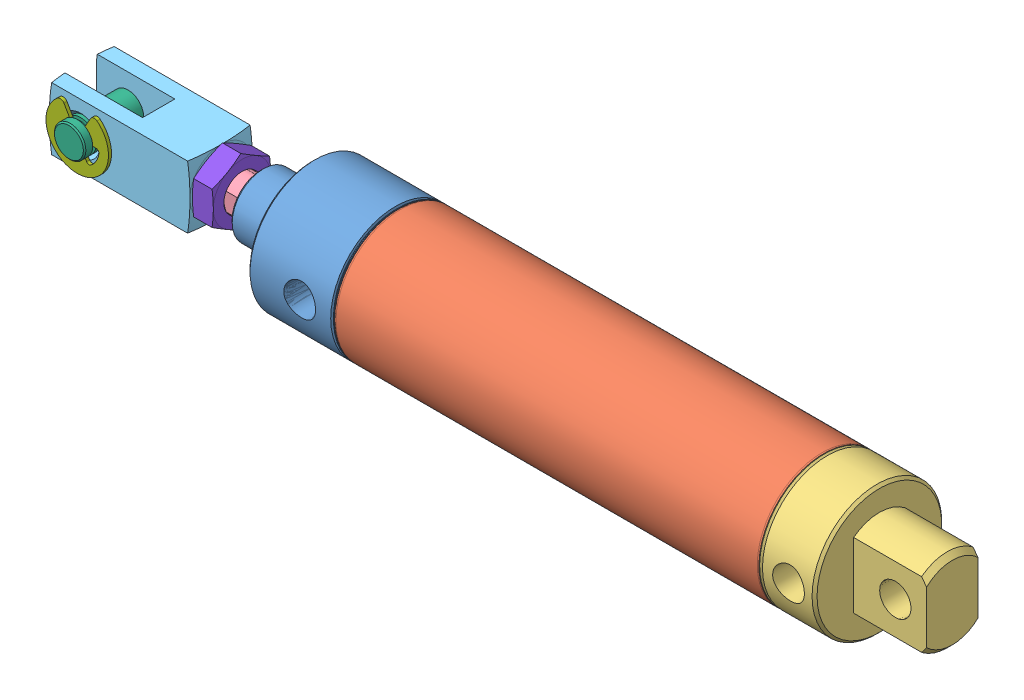
SolidWorks assembly 173_8-DP(F,D-231-1), configuration Default. Lengths in mm.
Overall size (266.64 39.54 39.54).
11 component instances, 10 part files, 26 mates.
Components (placement in the parent):
- 173_8-DPC(F,D-231-1)0000_0_dummy-1: 173_8-DPC(F,D-231-1)0000_0_dummy [Default] at origin
- 17R000-0_rod_guide-1: 17R000-0_rod_guide [Default] at origin size (47.62 39.54 39.54)
- 17R-5_10250C-1: 17R-5_10250C [Default] at (42.2275 0 0) size (131.44 39.54 39.54)
- 17P0000_rear_head-1: 17P0000_rear_head [Default] at (166.497 0 0) size (44.45 39.54 39.54)
- C-173_8-DP0_rod-1: C-173_8-DP0_rod [Default] x (1 0 0) z (0 0 -1) size (191.9 38.29 38.29)
- D-231-1-dummy-1: D-231-1-dummy [Default] at (-45.2628 0 0) x (1 0 0) z (0 0 -1)
- D-14053-1: D-14053 [Default] at (-45.2628 0 0) size (44.63 19.05 19.05)
- D-8383-1: D-8383 [Default] at (-45.2628 0 0) x (0 0 -1) z (-1 0 0) size (26.19 9.56 9.56)
- D-5867-1: D-5867 [Default] at (-45.2628 0 -10.1029) x (-1 0 0) z (0 0 1) size (19.05 17.19 0.93)
- D-5867-2: D-5867 [Default] at (-45.2628 0 10.1029) x (-1 0 0) z (0 0 1) size (19.05 17.19 0.93)
- D-154-1: D-154 [Default] at (-11.938 0 0) x (0 0 1) z (-1 0 0) size (17.53 20.24 6.35)
Mates (geometry in assembly coordinates):
- Distance2: distance = 0 mm aligned: plane of 17R000-0_rod_guide-1 through (0 0 0) normal (1 0 0); plane of 173_8-DPC(F,D-231-1)0000_0_dummy-1 through (0 0 0) normal (1 0 0)
- Coincident1: coincident aligned: line of 173_8-DPC(F,D-231-1)0000_0_dummy-1 through (80.9 0 0) axis (-1 0 0); line of 17R000-0_rod_guide-1 through (80.9 0 0) axis (-1 0 0)
- Angle3: planar angle = 0 rad aligned: plane of 17R000-0_rod_guide-1 through (0 0 0) normal (0 0 -1); plane of 173_8-DPC(F,D-231-1)0000_0_dummy-1 through (0 0 0) normal (0 0 -1)
- Distance4: distance = 0 mm aligned: plane of 17R-5_10250C-1 through (42.2275 0 0) normal (1 0 0); plane of 17R000-0_rod_guide-1 through (42.2275 0 0) normal (1 0 0)
- Coincident2: coincident aligned: line of 17R000-0_rod_guide-1 through (80.9 0 0) axis (-1 0 0); line of 17R-5_10250C-1 through (123.1275 0 0) axis (-1 0 0)
- Angle6: planar angle = 0 rad aligned: plane of 17R-5_10250C-1 through (42.2275 0 0) normal (0 0 -1); plane of 17R000-0_rod_guide-1 through (0 0 0) normal (0 0 -1)
- Distance6: distance = 0 mm aligned: plane of 17P0000_rear_head-1 through (171.831 0 0) normal (1 0 0); plane of 17R-5_10250C-1 through (171.831 0 0) normal (1 0 0)
- Coincident3: coincident aligned: line of 17R-5_10250C-1 through (123.1275 0 0) axis (-1 0 0); line of 17P0000_rear_head-1 through (247.397 0 0) axis (-1 0 0)
- Angle9: planar angle = 0.000031 rad aligned: plane of 17P0000_rear_head-1 through (166.497 0 0) normal (0 0 -1); plane of 17R-5_10250C-1 through (42.2275 0 0) normal (0 0 -1)
- LimitDistance2: limit distance = 0 mm aligned: plane of C-173_8-DP0_rod-1; plane of 17R000-0_rod_guide-1 through (0 0 0) normal (1 0 0)
- Coincident5: coincident aligned: line of 17R000-0_rod_guide-1 through (80.9 0 0) axis (-1 0 0); line of C-173_8-DP0_rod-1 through (80.9 0 0) axis (-1 0 0)
- Distance9: distance = 0 mm aligned: plane of D-231-1-dummy-1; plane of C-173_8-DP0_rod-1
- Coincident6: coincident aligned: line of C-173_8-DP0_rod-1 through (80.9 0 0) axis (-1 0 0); line of D-231-1-dummy-1 through (35.6372 0 0) axis (-1 0 0)
- Angle15: planar angle = 0 rad aligned: plane of D-231-1-dummy-1 through (-45.2628 0 0) normal (0 0 1); plane of C-173_8-DP0_rod-1 through (0 0 0) normal (0 0 1)
- Distance10: distance = 0 mm anti-aligned: plane of D-14053-1 through (-45.2628 0 0) normal (0 0 1); plane of D-231-1-dummy-1 through (-45.2628 0 0) normal (0 0 -1)
- Coincident7: coincident anti-aligned: line of D-231-1-dummy-1 through (-45.2628 0 -80.9) axis (0 0 1); line of D-14053-1 through (-45.2628 0 80.9) axis (0 0 -1)
- Angle18: planar angle = 0 rad aligned: plane of D-14053-1 through (-45.2628 0 0) normal (1 0 0); plane of D-231-1-dummy-1
- Coincident8: coincident anti-aligned: plane of D-14053-1 through (-45.2628 0 0) normal (0 0 1); plane of D-8383-1
- Coincident9: coincident anti-aligned: line of D-14053-1 through (-45.2628 0 80.9) axis (0 0 -1); line of D-8383-1 through (-45.2628 0 -80.9) axis (0 0 1)
- Coincident10: coincident anti-aligned: plane of D-8383-1; plane of D-5867-1 through (-45.2628 0 -10.1029) normal (0 0 1)
- Coincident11: coincident anti-aligned: line of D-8383-1 through (-45.2628 0 -80.9) axis (0 0 1); line of D-5867-1 through (-45.2628 0 70.7972) axis (0 0 -1)
- Coincident12: coincident anti-aligned: plane of D-8383-1; plane of D-5867-2 through (-45.2628 0 10.1029) normal (0 0 1)
- Coincident13: coincident anti-aligned: line of D-8383-1 through (-45.2628 0 -80.9) axis (0 0 1); line of D-5867-2 through (-45.2628 0 91.0028) axis (0 0 -1)
- Coincident14: coincident anti-aligned: plane of D-14053-1 through (-11.938 0 0) normal (1 0 0); plane of D-154-1 through (-11.938 0 0) normal (-1 0 0)
- Coincident15: coincident anti-aligned: line of D-14053-1 through (35.6372 0 0) axis (-1 0 0); line of D-154-1 through (-92.838 0 0) axis (1 0 0)
- Parallel1: parallel aligned: plane of 17P0000_rear_head-1 through (188.722 39.5351 7.8359) normal (0 0 1); plane of D-14053-1 through (-45.2628 0 9.525) normal (0 0 1)
